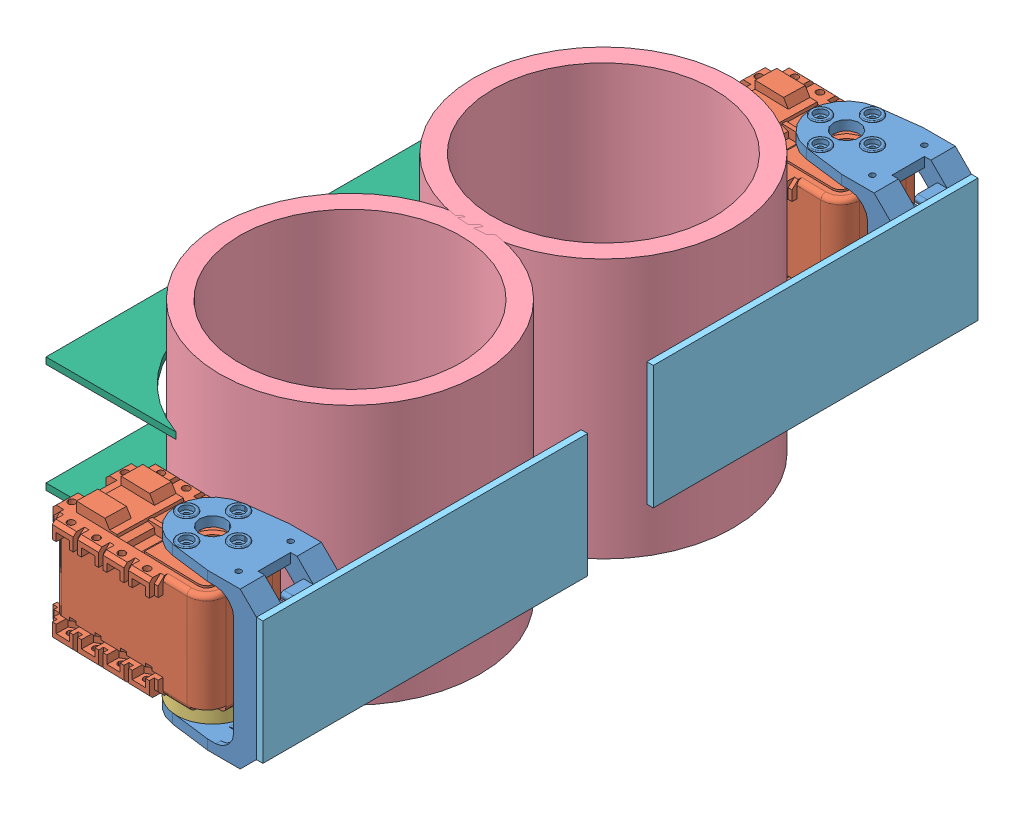
SolidWorks assembly pince_a_verre, configuration Défaut. Lengths in mm.
Overall size (98.19 80 228.37).
14 component instances, 6 part files, 27 mates.
Components (placement in the parent):
- F2-1: F2 [Défaut] at (17.2602 21.5869 90.7076) x (0 -1 0) z (1 0 0) size (48.81 25 37)
- F2-2: F2 [Défaut] at (17.2602 29.6206 -104.5027) x (0 -1 0) z (1 0 0) size (48.81 25 37)
- servomoteur_ax-12-1: servomoteur_ax-12 [Default] at (-4.5483 25.318 -107.6918) x (0.023393 0 -0.999726) z (0 -1 0) size (32 50.06 40.7)
  - AX-12_modif-1: AX-12_modif [Défaut] at (-2.6768 21.8769 -4.3025) size (32 50.06 38.01)
  - attache_ax-12-1: attache_ax-12 [Default] at (-2.6781 21.8771 12.6975) x (0.023393 0.999726 0) z (0 0 1) size (22 22 4.7)
- servomoteur_ax-12-2: servomoteur_ax-12 [Default] at (-4.5483 17.2844 87.5185) x (0.023393 0 -0.999726) z (0 -1 0) size (32 50.06 40.7)
  - AX-12_modif-1: AX-12_modif [Défaut] at (-2.6768 21.8769 -4.3025) size (32 50.06 38.01)
  - attache_ax-12-1: attache_ax-12 [Default] at (-2.6781 21.8771 12.6975) x (0.023393 0.999726 0) z (0 0 1) size (22 22 4.7)
- Verre-1: Verre [Défaut] at (1.0911 -11.2101 32.2363) x (1 0 0) z (0 1 0) size (80 80 80)
- Verre-2: Verre [Défaut] at (1.0911 -11.2101 -45.8136) x (1 0 0) z (0 1 0) size (80 80 80)
- plaque_serrage-1: plaque_serrage [Défaut] at (43.2602 14.4288 34.8931) x (0 0 -1) z (1 0 0) size (100 38 2)
- plaque_serrage-2: plaque_serrage [Défaut] at (43.2602 22.4625 -85.3172) x (0 0 -1) z (1 0 0) size (100 38 2)
- plaque_fixation-1: plaque_fixation [Défaut] at (-31.6026 46.2206 -13.1925) x (0 0 1) z (1 0 0) size (157.23 2 40)
- plaque_fixation-2: plaque_fixation [Défaut] at (-31.6026 12.6206 -13.1925) x (0 0 1) z (1 0 0) size (157.23 2 40)
Mates (geometry in assembly coordinates):
- Coaxiale3: concentric aligned: cylinder of F2-2 through (25.2602 53.6206 -104.5027) axis (0 1 0) radius 1.05; cylinder of servomoteur_ax-12-1/attache_ax-12-1 through (25.2602 8.6206 -104.5027) axis (0 1 0) radius 1.1
- Coaxiale4: concentric aligned: cylinder of F2-2 through (9.2602 53.6206 -104.5027) axis (0 1 0) radius 1.05; cylinder of servomoteur_ax-12-1/attache_ax-12-1 through (9.2602 8.6206 -104.5027) axis (0 1 0) radius 1.1
- Coïncidente2: coincident anti-aligned: plane of F2-2 through (17.2602 8.6206 -104.5027) normal (0 1 0); plane of servomoteur_ax-12-1/attache_ax-12-1 through (17.2602 8.6206 -104.5027) normal (0 -1 0)
- Coaxiale5: concentric aligned: cylinder of F2-1 through (25.2602 45.5869 90.7076) axis (0 1 0) radius 1.05; cylinder of servomoteur_ax-12-2/attache_ax-12-1 through (25.2602 0.5869 90.7076) axis (0 1 0) radius 1.1
- Coaxiale6: concentric aligned: cylinder of F2-1 through (9.2602 45.5869 90.7076) axis (0 1 0) radius 1.05; cylinder of servomoteur_ax-12-2/attache_ax-12-1 through (9.2602 0.5869 90.7076) axis (0 1 0) radius 1.1
- Coïncidente3: coincident anti-aligned: plane of F2-1 through (17.2602 0.5869 90.7076) normal (0 1 0); plane of servomoteur_ax-12-2/attache_ax-12-1 through (17.2602 0.5869 90.7076) normal (0 -1 0)
- Parallèle1: parallel: line of servomoteur_ax-12-2/AX-12_modif-1 through (-18.4993 10.5869 101.3728) axis (0 1 0); plane of assembly
- Parallèle7: parallel anti-aligned: plane of servomoteur_ax-12-1/AX-12_modif-1 through (-15.9643 10.6206 -94.8785) normal (0 -1 0); plane of assembly through (0 0 0) normal (0 1 0)
- Parallèle2: parallel aligned: plane of Verre-1 through (1.0911 68.7899 32.2363) normal (0 1 0); plane of assembly through (0 0 0) normal (0 1 0)
- Coïncidente11: coincident aligned: plane of Verre-1 through (1.0911 68.7899 32.2363) normal (0 1 0); plane of Verre-2 through (1.0911 68.7899 -45.8136) normal (0 1 0)
- Coïncidente12: coincident anti-aligned: plane of F2-1 through (43.2602 45.5869 78.2076) normal (1 0 0); plane of plaque_serrage-1 through (43.2602 2.5869 103.2076) normal (-1 0 0)
- Coïncidente13: coincident aligned: plane of F2-1 through (43.2602 45.5869 103.2076) normal (0 0 1); plane of plaque_serrage-1 through (45.2602 40.5869 103.2076) normal (0 0 1)
- Coïncidente14: coincident: line of F2-1 through (43.2602 40.5869 95.7076) axis (0 0 1); plane of plaque_serrage-1 through (45.2602 40.5869 103.2076) normal (0 1 0)
- Coïncidente15: coincident anti-aligned: plane of F2-2 through (43.2602 53.6206 -117.0027) normal (1 0 0); plane of plaque_serrage-2 through (43.2602 10.6206 -17.0027) normal (-1 0 0)
- Coïncidente16: coincident aligned: plane of F2-2 through (28.2602 53.6206 -117.0027) normal (0 0 -1); plane of plaque_serrage-2 through (45.2602 48.6206 -117.0027) normal (0 0 -1)
- Coïncidente17: coincident aligned: line of F2-2 through (43.2602 48.6206 -117.0027) axis (0 0 1); line of plaque_serrage-2 through (43.2602 48.6206 -117.0027) axis (0 0 1)
- Parallèle5: parallel aligned: plane of plaque_fixation-1 through (1.0911 46.2206 -45.8136) normal (0 1 0); plane of assembly through (0 0 0) normal (0 1 0)
- Parallèle6: parallel anti-aligned: plane of plaque_fixation-1 through (-52.9301 44.2206 -85.404) normal (-1 0 0); plane of assembly through (0 0 0) normal (1 0 0)
- Coïncidente23: coincident aligned: plane of servomoteur_ax-12-1/AX-12_modif-1 through (-15.8076 46.2206 -115.6805) normal (0 1 0); plane of plaque_fixation-1 through (1.0911 46.2206 -45.8136) normal (0 1 0)
- Coïncidente27: coincident aligned: plane of servomoteur_ax-12-1/AX-12_modif-1 through (-15.9643 10.6206 -94.8785) normal (0 -1 0); plane of plaque_fixation-2 through (1.0911 10.6206 -45.8136) normal (0 -1 0)
- Coïncidente28: coincident aligned: plane of plaque_fixation-1 through (-52.9301 44.2206 -85.404) normal (0 0 -1); plane of plaque_fixation-2 through (-52.9301 10.6206 -85.404) normal (0 0 -1)
- Coïncidente29: coincident aligned: plane of plaque_fixation-1 through (-52.9301 44.2206 -85.404) normal (-1 0 0); plane of plaque_fixation-2 through (-52.9301 10.6206 -85.404) normal (-1 0 0)
- Parallèle8: parallel anti-aligned: plane of servomoteur_ax-12-2/AX-12_modif-1 through (-15.9643 2.5869 100.3318) normal (0 -1 0); plane of assembly through (0 0 0) normal (0 1 0)
- Distance2: distance = 22.5693 mm aligned: plane of Verre-1 through (1.0911 68.7899 32.2363) normal (0 1 0); plane of plaque_fixation-1 through (1.0911 46.2206 -45.8136) normal (0 1 0)
- Coïncidente34: coincident aligned: plane of plaque_serrage-1 through (45.2602 2.5869 103.2076) normal (1 0 0); plane of plaque_serrage-2 through (45.2602 10.6206 -17.0027) normal (1 0 0)
- Coaxiale7: concentric anti-aligned: cylinder of Verre-1 through (1.0911 68.7899 32.2363) axis (0 -1 0) radius 40; cylinder of plaque_fixation-1 through (1.0911 44.2206 32.2363) axis (0 1 0) radius 42
- Coaxiale8: concentric anti-aligned: cylinder of Verre-2 through (1.0911 68.7899 -45.8136) axis (0 -1 0) radius 40; cylinder of plaque_fixation-1 through (1.0911 44.2206 -45.8136) axis (0 1 0) radius 42
